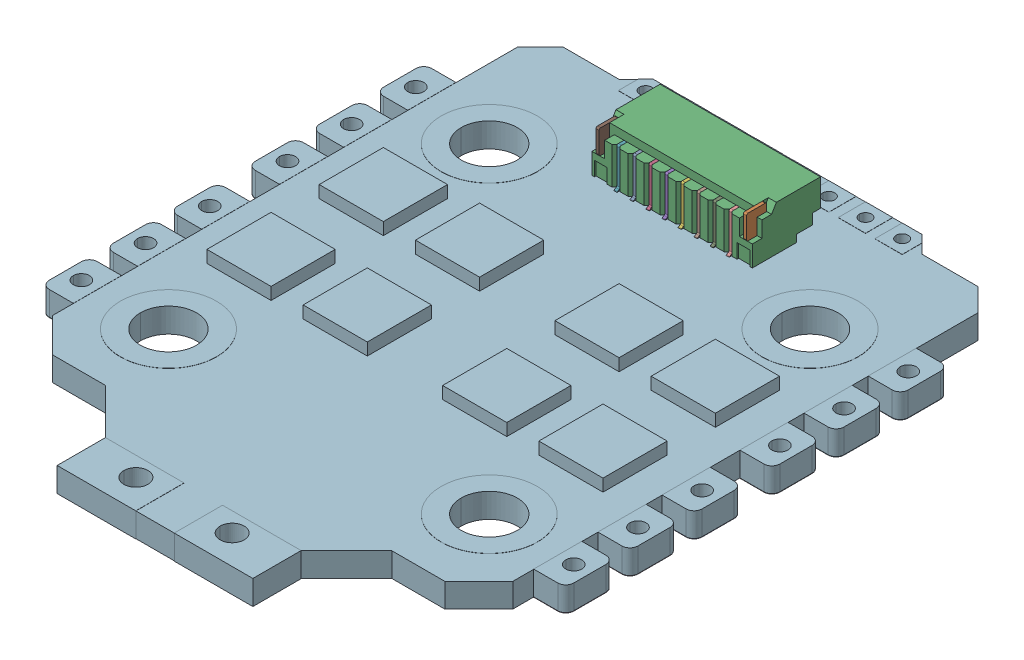
SolidWorks assembly Tekko32 F4 4in1 Mini 45A ESC V1.3 v4, configuration Défaut. Lengths in mm.
Overall size (32.7 6.36 39.43).
2 component instances, 2 part files, 0 mates.
Components (placement in the parent):
- BM8B-SRSS-TB v1-1: BM8B-SRSS-TB v1 [Défaut] at (-3.499 1.5 -32.2268) x (1 0 0) z (0 0 -1) size (10 3.6 4.3)
- Tekko32 F4 4in1 Mini 45A ESC V1.3 v4-1: Tekko32 F4 4in1 Mini 45A ESC V1.3 v4 [Défaut] at origin size (32.7 4.22 39.43)
